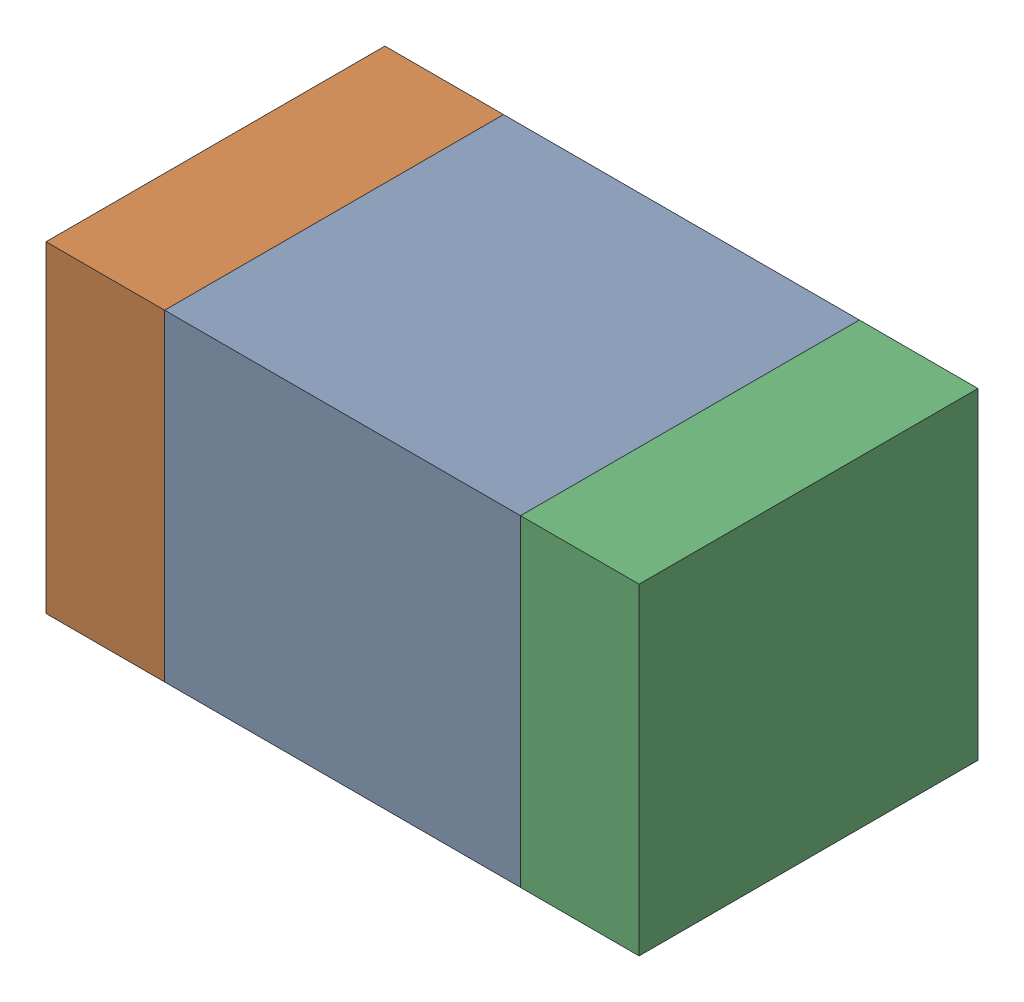
SolidWorks assembly C123_2PCB, configuration Default. Lengths in mm.
Overall size (1.75 0.95 1).
6 component instances, 2 part files, 0 mates.
Components (placement in the parent):
- 761616112-1: 761616112 [Default] at (106.6 101.5 0) size (1.05 0.95 1)
  - Extruded_14-1: Extruded_14 [Default] at origin size (1.05 0.95 1)
- 761616248-1: 761616248 [Default] at (105.9 101.5 0) size (0.35 0.95 1)
  - Extruded_15-1: Extruded_15 [Default] at origin size (0.35 0.95 1)
- 761616248-2: 761616248 [Default] at (107.3 101.5 0) size (0.35 0.95 1)
  - Extruded_15-1: Extruded_15 [Default] at origin size (0.35 0.95 1)
